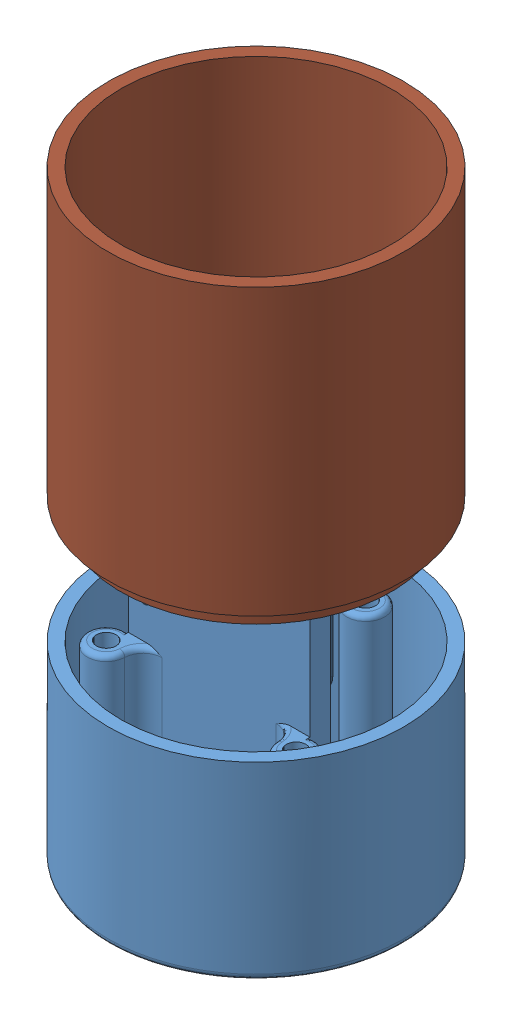
SolidWorks assembly 机器人顶部UWB基站装配, configuration 默认. Lengths in mm.
Overall size (60.56 94.97 60.56).
234 component instances, 29 part files, 4 mates.
Components (placement in the parent):
- UWB天线支架-TWR-1: UWB天线支架-TWR [默认] at (-22.1271 -22.7514 62) size (46.7 62 46.7)
- GeekUWB-TWR.step-1: GeekUWB-TWR.step [默认] at (68.161 -65.1454 64.2043) x (-1 0 0) z (0 0 -1) size (28.7 41.1 6.58)
  - R14.step-1: R14.step [默认] at origin size (0.5 1 0.35)
    - 5863272896.step-1: 5863272896.step [默认] at (77.2159 80.1371 0) x (0 1 0) z (0 0 1) size (1 0.5 0.35)
      - Terminal.step-1: Terminal.step [默认] at (-0.5 -0.25 0) size (0.25 0.5 0.35)
        - Open_CASCADE_STEP_translator_6.8_20.2.1.step-1: Open_CASCADE_STEP_translator_6.8_20.2.1.step [默认] at origin size (0.25 0.5 0.35)
      - Terminal.step-2: Terminal.step [默认] at (0.5 0.25 0) x (-1 0 0) z (0 0 1) size (0.25 0.5 0.35)
        - Open_CASCADE_STEP_translator_6.8_20.2.1.step-1: Open_CASCADE_STEP_translator_6.8_20.2.1.step [默认] at origin size (0.25 0.5 0.35)
      - Mid_Body.step-1: Mid_Body.step [默认] at (-0.5 -0.25 0) size (0.93 0.5 0.28)
      - Mark.step-1: Mark.step [默认] at (-0.25 -0.25 0.315) size (0.5 0.5 0.03)
  - C7.step-1: C7.step [默认] at origin size (1 0.5 0.5)
    - 5863272512.step-1: 5863272512.step [默认] at (78.8669 91.4399 0) x (-1 0 0) z (0 0 1) size (1 0.5 0.5)
      - Terminal-1.step-1: Terminal-1.step [默认] at (-0.5 -0.25 0) size (1 0.5 0.5)
        - Open_CASCADE_STEP_translator_6.8_54.1.1.step-1: Open_CASCADE_STEP_translator_6.8_54.1.1.step [默认] at origin size (0.25 0.5 0.5)
        - Open_CASCADE_STEP_translator_6.8_54.1.2.step-1: Open_CASCADE_STEP_translator_6.8_54.1.2.step [默认] at origin size (0.25 0.5 0.5)
      - Mid_Body-0.step-1: Mid_Body-0.step [默认] at (-0.5 -0.25 0) size (0.5 0.5 0.5)
        - Open_CASCADE_STEP_translator_6.8_54.2.1.step-1: Open_CASCADE_STEP_translator_6.8_54.2.1.step [默认] at origin size (0.5 0.5 0.5)
  - Y1.step-1: Y1.step [默认] at origin size (1.31 3.21 0.71)
    - 123123123.step-1: 123123123.step [默认] at (79.121 88.3921 0) x (0 1 0) z (0 0 1) size (3.21 1.31 0.71)
  - R7.step-1: R7.step [默认] at origin size (1 0.5 0.35)
    - 5863271360.step-1: 5863271360.step [默认] at (88.0109 97.2819 0) x (-1 0 0) z (0 0 1) size (1 0.5 0.35)
      - Terminal-2.step-1: Terminal-2.step [默认] at (-0.5 -0.25 0) size (0.25 0.5 0.35)
        - Open_CASCADE_STEP_translator_6.8_20.2.1-1.step-1: Open_CASCADE_STEP_translator_6.8_20.2.1-1.step [默认] at origin size (0.25 0.5 0.35)
      - Terminal-2.step-2: Terminal-2.step [默认] at (0.5 0.25 0) x (-1 0 0) z (0 0 1) size (0.25 0.5 0.35)
        - Open_CASCADE_STEP_translator_6.8_20.2.1-1.step-1: Open_CASCADE_STEP_translator_6.8_20.2.1-1.step [默认] at origin size (0.25 0.5 0.35)
      - Mid_Body-2.step-1: Mid_Body-2.step [默认] at (-0.5 -0.25 0) size (0.93 0.5 0.28)
      - Mark-3.step-1: Mark-3.step [默认] at (-0.25 -0.25 0.315) size (0.5 0.5 0.03)
  - R10.step-1: R10.step [默认] at origin size (1 0.5 0.35)
    - 5863271744.step-1: 5863271744.step [默认] at (101.3461 99.0601 0) x (1 0 0) z (0 0 1) size (1 0.5 0.35)
      - Terminal-3.step-1: Terminal-3.step [默认] at (-0.5 -0.25 0) size (0.25 0.5 0.35)
        - Open_CASCADE_STEP_translator_6.8_20.2.1-4.step-1: Open_CASCADE_STEP_translator_6.8_20.2.1-4.step [默认] at origin size (0.25 0.5 0.35)
      - Terminal-3.step-2: Terminal-3.step [默认] at (0.5 0.25 0) x (-1 0 0) z (0 0 1) size (0.25 0.5 0.35)
        - Open_CASCADE_STEP_translator_6.8_20.2.1-4.step-1: Open_CASCADE_STEP_translator_6.8_20.2.1-4.step [默认] at origin size (0.25 0.5 0.35)
      - Mid_Body-5.step-1: Mid_Body-5.step [默认] at (-0.5 -0.25 0) size (0.93 0.5 0.28)
      - Mark-6.step-1: Mark-6.step [默认] at (-0.25 -0.25 0.315) size (0.5 0.5 0.03)
  - R9.step-1: R9.step [默认] at origin size (1 0.5 0.35)
    - 5863271744.step-1: 5863271744.step [默认] at (101.3461 100.2031 0) x (1 0 0) z (0 0 1) size (1 0.5 0.35)
      - Terminal-3.step-1: Terminal-3.step [默认] at (-0.5 -0.25 0) size (0.25 0.5 0.35)
        - Open_CASCADE_STEP_translator_6.8_20.2.1-4.step-1: Open_CASCADE_STEP_translator_6.8_20.2.1-4.step [默认] at origin size (0.25 0.5 0.35)
      - Terminal-3.step-2: Terminal-3.step [默认] at (0.5 0.25 0) x (-1 0 0) z (0 0 1) size (0.25 0.5 0.35)
        - Open_CASCADE_STEP_translator_6.8_20.2.1-4.step-1: Open_CASCADE_STEP_translator_6.8_20.2.1-4.step [默认] at origin size (0.25 0.5 0.35)
      - Mid_Body-5.step-1: Mid_Body-5.step [默认] at (-0.5 -0.25 0) size (0.93 0.5 0.28)
      - Mark-6.step-1: Mark-6.step [默认] at (-0.25 -0.25 0.315) size (0.5 0.5 0.03)
  - R8.step-1: R8.step [默认] at origin size (1 0.5 0.35)
    - 5863271360.step-1: 5863271360.step [默认] at (82.0419 87.8839 0) x (-1 0 0) z (0 0 1) size (1 0.5 0.35)
      - Terminal-2.step-1: Terminal-2.step [默认] at (-0.5 -0.25 0) size (0.25 0.5 0.35)
        - Open_CASCADE_STEP_translator_6.8_20.2.1-1.step-1: Open_CASCADE_STEP_translator_6.8_20.2.1-1.step [默认] at origin size (0.25 0.5 0.35)
      - Terminal-2.step-2: Terminal-2.step [默认] at (0.5 0.25 0) x (-1 0 0) z (0 0 1) size (0.25 0.5 0.35)
        - Open_CASCADE_STEP_translator_6.8_20.2.1-1.step-1: Open_CASCADE_STEP_translator_6.8_20.2.1-1.step [默认] at origin size (0.25 0.5 0.35)
      - Mid_Body-2.step-1: Mid_Body-2.step [默认] at (-0.5 -0.25 0) size (0.93 0.5 0.28)
      - Mark-3.step-1: Mark-3.step [默认] at (-0.25 -0.25 0.315) size (0.5 0.5 0.03)
  - R6.step-1: R6.step [默认] at origin size (1 0.5 0.35)
    - 5863271744.step-1: 5863271744.step [默认] at (100.7111 89.2811 0) x (1 0 0) z (0 0 1) size (1 0.5 0.35)
      - Terminal-3.step-1: Terminal-3.step [默认] at (-0.5 -0.25 0) size (0.25 0.5 0.35)
        - Open_CASCADE_STEP_translator_6.8_20.2.1-4.step-1: Open_CASCADE_STEP_translator_6.8_20.2.1-4.step [默认] at origin size (0.25 0.5 0.35)
      - Terminal-3.step-2: Terminal-3.step [默认] at (0.5 0.25 0) x (-1 0 0) z (0 0 1) size (0.25 0.5 0.35)
        - Open_CASCADE_STEP_translator_6.8_20.2.1-4.step-1: Open_CASCADE_STEP_translator_6.8_20.2.1-4.step [默认] at origin size (0.25 0.5 0.35)
      - Mid_Body-5.step-1: Mid_Body-5.step [默认] at (-0.5 -0.25 0) size (0.93 0.5 0.28)
      - Mark-6.step-1: Mark-6.step [默认] at (-0.25 -0.25 0.315) size (0.5 0.5 0.03)
  - R5.step-1: R5.step [默认] at origin size (1 0.5 0.35)
    - 5863271744.step-1: 5863271744.step [默认] at (101.3461 101.3461 0) x (1 0 0) z (0 0 1) size (1 0.5 0.35)
      - Terminal-3.step-1: Terminal-3.step [默认] at (-0.5 -0.25 0) size (0.25 0.5 0.35)
        - Open_CASCADE_STEP_translator_6.8_20.2.1-4.step-1: Open_CASCADE_STEP_translator_6.8_20.2.1-4.step [默认] at origin size (0.25 0.5 0.35)
      - Terminal-3.step-2: Terminal-3.step [默认] at (0.5 0.25 0) x (-1 0 0) z (0 0 1) size (0.25 0.5 0.35)
        - Open_CASCADE_STEP_translator_6.8_20.2.1-4.step-1: Open_CASCADE_STEP_translator_6.8_20.2.1-4.step [默认] at origin size (0.25 0.5 0.35)
      - Mid_Body-5.step-1: Mid_Body-5.step [默认] at (-0.5 -0.25 0) size (0.93 0.5 0.28)
      - Mark-6.step-1: Mark-6.step [默认] at (-0.25 -0.25 0.315) size (0.5 0.5 0.03)
  - R2.step-1: R2.step [默认] at origin size (1 0.5 0.35)
    - 5863271744.step-1: 5863271744.step [默认] at (80.8991 85.4711 0) x (1 0 0) z (0 0 1) size (1 0.5 0.35)
      - Terminal-3.step-1: Terminal-3.step [默认] at (-0.5 -0.25 0) size (0.25 0.5 0.35)
        - Open_CASCADE_STEP_translator_6.8_20.2.1-4.step-1: Open_CASCADE_STEP_translator_6.8_20.2.1-4.step [默认] at origin size (0.25 0.5 0.35)
      - Terminal-3.step-2: Terminal-3.step [默认] at (0.5 0.25 0) x (-1 0 0) z (0 0 1) size (0.25 0.5 0.35)
        - Open_CASCADE_STEP_translator_6.8_20.2.1-4.step-1: Open_CASCADE_STEP_translator_6.8_20.2.1-4.step [默认] at origin size (0.25 0.5 0.35)
      - Mid_Body-5.step-1: Mid_Body-5.step [默认] at (-0.5 -0.25 0) size (0.93 0.5 0.28)
      - Mark-6.step-1: Mark-6.step [默认] at (-0.25 -0.25 0.315) size (0.5 0.5 0.03)
  - R3.step-1: R3.step [默认] at origin size (1 0.5 0.35)
    - 5863271744.step-1: 5863271744.step [默认] at (80.8991 84.4551 0) x (1 0 0) z (0 0 1) size (1 0.5 0.35)
      - Terminal-3.step-1: Terminal-3.step [默认] at (-0.5 -0.25 0) size (0.25 0.5 0.35)
        - Open_CASCADE_STEP_translator_6.8_20.2.1-4.step-1: Open_CASCADE_STEP_translator_6.8_20.2.1-4.step [默认] at origin size (0.25 0.5 0.35)
      - Terminal-3.step-2: Terminal-3.step [默认] at (0.5 0.25 0) x (-1 0 0) z (0 0 1) size (0.25 0.5 0.35)
        - Open_CASCADE_STEP_translator_6.8_20.2.1-4.step-1: Open_CASCADE_STEP_translator_6.8_20.2.1-4.step [默认] at origin size (0.25 0.5 0.35)
      - Mid_Body-5.step-1: Mid_Body-5.step [默认] at (-0.5 -0.25 0) size (0.93 0.5 0.28)
      - Mark-6.step-1: Mark-6.step [默认] at (-0.25 -0.25 0.315) size (0.5 0.5 0.03)
  - R1.step-1: R1.step [默认] at origin size (0.5 1 0.35)
    - 5863272896.step-1: 5863272896.step [默认] at (78.294 80.1531 0) x (0 1 0) z (0 0 1) size (1 0.5 0.35)
      - Terminal.step-1: Terminal.step [默认] at (-0.5 -0.25 0) size (0.25 0.5 0.35)
        - Open_CASCADE_STEP_translator_6.8_20.2.1.step-1: Open_CASCADE_STEP_translator_6.8_20.2.1.step [默认] at origin size (0.25 0.5 0.35)
      - Terminal.step-2: Terminal.step [默认] at (0.5 0.25 0) x (-1 0 0) z (0 0 1) size (0.25 0.5 0.35)
        - Open_CASCADE_STEP_translator_6.8_20.2.1.step-1: Open_CASCADE_STEP_translator_6.8_20.2.1.step [默认] at origin size (0.25 0.5 0.35)
      - Mid_Body.step-1: Mid_Body.step [默认] at (-0.5 -0.25 0) size (0.93 0.5 0.28)
      - Mark.step-1: Mark.step [默认] at (-0.25 -0.25 0.315) size (0.5 0.5 0.03)
  - R4.step-1: R4.step [默认] at origin size (1 0.5 0.35)
    - 5863271744.step-1: 5863271744.step [默认] at (80.8991 83.4391 0) x (1 0 0) z (0 0 1) size (1 0.5 0.35)
      - Terminal-3.step-1: Terminal-3.step [默认] at (-0.5 -0.25 0) size (0.25 0.5 0.35)
        - Open_CASCADE_STEP_translator_6.8_20.2.1-4.step-1: Open_CASCADE_STEP_translator_6.8_20.2.1-4.step [默认] at origin size (0.25 0.5 0.35)
      - Terminal-3.step-2: Terminal-3.step [默认] at (0.5 0.25 0) x (-1 0 0) z (0 0 1) size (0.25 0.5 0.35)
        - Open_CASCADE_STEP_translator_6.8_20.2.1-4.step-1: Open_CASCADE_STEP_translator_6.8_20.2.1-4.step [默认] at origin size (0.25 0.5 0.35)
      - Mid_Body-5.step-1: Mid_Body-5.step [默认] at (-0.5 -0.25 0) size (0.93 0.5 0.28)
      - Mark-6.step-1: Mark-6.step [默认] at (-0.25 -0.25 0.315) size (0.5 0.5 0.03)
  - R13.step-1: R13.step [默认] at origin size (1 0.5 0.35)
    - 5863271360.step-1: 5863271360.step [默认] at (98.8059 91.4399 0) x (-1 0 0) z (0 0 1) size (1 0.5 0.35)
      - Terminal-2.step-1: Terminal-2.step [默认] at (-0.5 -0.25 0) size (0.25 0.5 0.35)
        - Open_CASCADE_STEP_translator_6.8_20.2.1-1.step-1: Open_CASCADE_STEP_translator_6.8_20.2.1-1.step [默认] at origin size (0.25 0.5 0.35)
      - Terminal-2.step-2: Terminal-2.step [默认] at (0.5 0.25 0) x (-1 0 0) z (0 0 1) size (0.25 0.5 0.35)
        - Open_CASCADE_STEP_translator_6.8_20.2.1-1.step-1: Open_CASCADE_STEP_translator_6.8_20.2.1-1.step [默认] at origin size (0.25 0.5 0.35)
      - Mid_Body-2.step-1: Mid_Body-2.step [默认] at (-0.5 -0.25 0) size (0.93 0.5 0.28)
      - Mark-3.step-1: Mark-3.step [默认] at (-0.25 -0.25 0.315) size (0.5 0.5 0.03)
  - R12.step-1: R12.step [默认] at origin size (0.5 1 0.35)
    - 5863271552.step-1: 5863271552.step [默认] at (101.2191 86.7769 0) x (0 -1 0) z (0 0 1) size (1 0.5 0.35)
      - Terminal-4.step-1: Terminal-4.step [默认] at (-0.5 -0.25 0) size (0.25 0.5 0.35)
        - Open_CASCADE_STEP_translator_6.8_20.2.1-7.step-1: Open_CASCADE_STEP_translator_6.8_20.2.1-7.step [默认] at origin size (0.25 0.5 0.35)
      - Terminal-4.step-2: Terminal-4.step [默认] at (0.5 0.25 0) x (-1 0 0) z (0 0 1) size (0.25 0.5 0.35)
        - Open_CASCADE_STEP_translator_6.8_20.2.1-7.step-1: Open_CASCADE_STEP_translator_6.8_20.2.1-7.step [默认] at origin size (0.25 0.5 0.35)
      - Mid_Body-8.step-1: Mid_Body-8.step [默认] at (-0.5 -0.25 0) size (0.93 0.5 0.28)
      - Mark-9.step-1: Mark-9.step [默认] at (-0.25 -0.25 0.315) size (0.5 0.5 0.03)
  - R11.step-1: R11.step [默认] at origin size (1 0.5 0.35)
    - 5863271744.step-1: 5863271744.step [默认] at (90.9941 97.3479 0) x (1 0 0) z (0 0 1) size (1 0.5 0.35)
      - Terminal-3.step-1: Terminal-3.step [默认] at (-0.5 -0.25 0) size (0.25 0.5 0.35)
        - Open_CASCADE_STEP_translator_6.8_20.2.1-4.step-1: Open_CASCADE_STEP_translator_6.8_20.2.1-4.step [默认] at origin size (0.25 0.5 0.35)
      - Terminal-3.step-2: Terminal-3.step [默认] at (0.5 0.25 0) x (-1 0 0) z (0 0 1) size (0.25 0.5 0.35)
        - Open_CASCADE_STEP_translator_6.8_20.2.1-4.step-1: Open_CASCADE_STEP_translator_6.8_20.2.1-4.step [默认] at origin size (0.25 0.5 0.35)
      - Mid_Body-5.step-1: Mid_Body-5.step [默认] at (-0.5 -0.25 0) size (0.93 0.5 0.28)
      - Mark-6.step-1: Mark-6.step [默认] at (-0.25 -0.25 0.315) size (0.5 0.5 0.03)
  - D4.step-1: D4.step [默认] at origin size (1.01 0.5 0.45)
    - User_Library-led_0402LED0402_red_.step-1: User_Library-led_0402LED0402_red_.step [默认] at (98.6791 89.281 0) x (1 0 0) z (0 0 1) size (1.01 0.5 0.45)
  - D1.step-1: D1.step [默认] at origin size (1.01 0.5 0.45)
    - User_Library-led_0402LED0402_red_.step-1: User_Library-led_0402LED0402_red_.step [默认] at (99.3141 100.203 0) x (1 0 0) z (0 0 1) size (1.01 0.5 0.45)
  - D2.step-1: D2.step [默认] at origin size (1.01 0.5 0.45)
    - User_Library-led_0402LED0402_red_.step-1: User_Library-led_0402LED0402_red_.step [默认] at (99.3141 99.06 0) x (1 0 0) z (0 0 1) size (1.01 0.5 0.45)
  - D3.step-1: D3.step [默认] at origin size (1.01 0.5 0.45)
    - User_Library-led_0402LED0402_red_.step-1: User_Library-led_0402LED0402_red_.step [默认] at (99.3141 101.346 0) x (1 0 0) z (0 0 1) size (1.01 0.5 0.45)
  - C5.step-1: C5.step [默认] at origin size (0.5 1 0.5)
    - 5863270784.step-1: 5863270784.step [默认] at (98.6791 96.5199 0) x (0 -1 0) z (0 0 1) size (1 0.5 0.5)
      - Terminal-5.step-1: Terminal-5.step [默认] at (-0.5 -0.25 0) size (1 0.5 0.5)
        - Open_CASCADE_STEP_translator_6.8_54.1.1-10.step-1: Open_CASCADE_STEP_translator_6.8_54.1.1-10.step [默认] at origin size (0.25 0.5 0.5)
        - Open_CASCADE_STEP_translator_6.8_54.1.2-11.step-1: Open_CASCADE_STEP_translator_6.8_54.1.2-11.step [默认] at origin size (0.25 0.5 0.5)
      - Mid_Body-1.step-1: Mid_Body-1.step [默认] at (-0.5 -0.25 0) size (0.5 0.5 0.5)
        - Open_CASCADE_STEP_translator_6.8_54.2.1-12.step-1: Open_CASCADE_STEP_translator_6.8_54.2.1-12.step [默认] at origin size (0.5 0.5 0.5)
  - C6.step-1: C6.step [默认] at origin size (1 0.5 0.5)
    - 5863272512.step-1: 5863272512.step [默认] at (82.0419 88.9126 0) x (-1 0 0) z (0 0 1) size (1 0.5 0.5)
      - Terminal-1.step-1: Terminal-1.step [默认] at (-0.5 -0.25 0) size (1 0.5 0.5)
        - Open_CASCADE_STEP_translator_6.8_54.1.1.step-1: Open_CASCADE_STEP_translator_6.8_54.1.1.step [默认] at origin size (0.25 0.5 0.5)
        - Open_CASCADE_STEP_translator_6.8_54.1.2.step-1: Open_CASCADE_STEP_translator_6.8_54.1.2.step [默认] at origin size (0.25 0.5 0.5)
      - Mid_Body-0.step-1: Mid_Body-0.step [默认] at (-0.5 -0.25 0) size (0.5 0.5 0.5)
        - Open_CASCADE_STEP_translator_6.8_54.2.1.step-1: Open_CASCADE_STEP_translator_6.8_54.2.1.step [默认] at origin size (0.5 0.5 0.5)
  - C4.step-1: C4.step [默认] at origin size (1.6 0.81 0.81)
    - C0603_3D.step-1: C0603_3D.step [默认] at (100.7109 96.3929 0) x (-1 0 0) z (0 0 1) size (1.6 0.81 0.81)
  - C3.step-1: C3.step [默认] at origin size (0.5 1 0.5)
    - 5863270784.step-1: 5863270784.step [默认] at (100.0761 86.7849 0) x (0 -1 0) z (0 0 1) size (1 0.5 0.5)
      - Terminal-5.step-1: Terminal-5.step [默认] at (-0.5 -0.25 0) size (1 0.5 0.5)
        - Open_CASCADE_STEP_translator_6.8_54.1.1-10.step-1: Open_CASCADE_STEP_translator_6.8_54.1.1-10.step [默认] at origin size (0.25 0.5 0.5)
        - Open_CASCADE_STEP_translator_6.8_54.1.2-11.step-1: Open_CASCADE_STEP_translator_6.8_54.1.2-11.step [默认] at origin size (0.25 0.5 0.5)
      - Mid_Body-1.step-1: Mid_Body-1.step [默认] at (-0.5 -0.25 0) size (0.5 0.5 0.5)
        - Open_CASCADE_STEP_translator_6.8_54.2.1-12.step-1: Open_CASCADE_STEP_translator_6.8_54.2.1-12.step [默认] at origin size (0.5 0.5 0.5)
  - C2.step-1: C2.step [默认] at origin size (0.81 1.6 0.81)
    - C0603_3D.step-1: C0603_3D.step [默认] at (98.5521 86.9949 0) x (0 -1 0) z (0 0 1) size (1.6 0.81 0.81)
  - C1.step-1: C1.step [默认] at origin size (1.6 0.81 0.81)
    - C0603_3D.step-1: C0603_3D.step [默认] at (78.9939 92.8369 0) x (-1 0 0) z (0 0 1) size (1.6 0.81 0.81)
  - USB.step-1: USB.step [默认] at origin size (8.96 7.76 4.27)
    - 1.step-1: 1.step [默认] at (98.1049 122.7063 3.5) x (1 0 0) z (0 0 -1) size (8.96 7.76 4.27)
  - U3.step-1: U3.step [默认] at origin size (13.2 23 2.9)
    - DWM1000_Module.step-1: DWM1000_Module.step [默认] at (90.301 102.0509 -0.4115) x (-1 0 0) z (0 -1 0) size (13.2 2.9 23)
  - U2.step-1: U2.step [默认] at origin size (2.9 2.8 1.2)
    - PCB1.step-1: PCB1.step [默认] at (80.4724 95.505 0) x (0 1 0) z (0 0 1) size (2.8 2.9 1.2)
  - U1.step-1: U1.step [默认] at origin size (12.01 12.01 1.45)
    - LQFP64-10x10.step-1: LQFP64-10x10.step [默认] at (90.2971 89.5349 0) x (0 -1 0) z (0 0 1) size (12.01 12.01 1.45)
      - LQFP64-10X10_1_AF0_ASM.step-1: LQFP64-10X10_1_AF0_ASM.step [默认] at origin size (12.01 12.01 1.45)
        - _0_25_100.step-1: _0_25_100.step [默认] at (-5 2.75 0.75) x (0 1 0) z (0 0 1) size (0.25 1 0.8)
        - _0_25_100.step-2: _0_25_100.step [默认] at (5 -1.25 0.75) x (0 -1 0) z (0 0 1) size (0.25 1 0.8)
        - _0_25_100.step-3: _0_25_100.step [默认] at (-0.75 5 0.75) size (0.25 1 0.8)
        - _0_25_100.step-4: _0_25_100.step [默认] at (-5 -2.75 0.75) x (0 1 0) z (0 0 1) size (0.25 1 0.8)
        - _0_25_100.step-5: _0_25_100.step [默认] at (-2.75 -5 0.75) x (-1 0 0) z (0 0 1) size (0.25 1 0.8)
        - _0_25_100.step-6: _0_25_100.step [默认] at (2.75 -5 0.75) x (-1 0 0) z (0 0 1) size (0.25 1 0.8)
        - _0_25_100.step-7: _0_25_100.step [默认] at (-5 3.75 0.75) x (0 1 0) z (0 0 1) size (0.25 1 0.8)
        - _0_25_100.step-8: _0_25_100.step [默认] at (5 -2.25 0.75) x (0 -1 0) z (0 0 1) size (0.25 1 0.8)
        - _0_25_100.step-9: _0_25_100.step [默认] at (0.25 5 0.75) size (0.25 1 0.8)
        - _0_25_100.step-10: _0_25_100.step [默认] at (-5 -1.75 0.75) x (0 1 0) z (0 0 1) size (0.25 1 0.8)
        - _0_25_100.step-11: _0_25_100.step [默认] at (5 3.25 0.75) x (0 -1 0) z (0 0 1) size (0.25 1 0.8)
        - _0_25_100.step-12: _0_25_100.step [默认] at (-0.25 -5 0.75) x (-1 0 0) z (0 0 1) size (0.25 1 0.8)
        - _0_25_100.step-13: _0_25_100.step [默认] at (5 -3.25 0.75) x (0 -1 0) z (0 0 1) size (0.25 1 0.8)
        - _0_25_100.step-14: _0_25_100.step [默认] at (1.25 5 0.75) size (0.25 1 0.8)
        - _0_25_100.step-15: _0_25_100.step [默认] at (-5 -0.75 0.75) x (0 1 0) z (0 0 1) size (0.25 1 0.8)
        - _0_25_100.step-16: _0_25_100.step [默认] at (5 2.25 0.75) x (0 -1 0) z (0 0 1) size (0.25 1 0.8)
        - _0_25_100.step-17: _0_25_100.step [默认] at (-3.25 -5 0.75) x (-1 0 0) z (0 0 1) size (0.25 1 0.8)
        - _0_25_100.step-18: _0_25_100.step [默认] at (2.25 -5 0.75) x (-1 0 0) z (0 0 1) size (0.25 1 0.8)
        - _0_25_100.step-19: _0_25_100.step [默认] at (2.25 5 0.75) size (0.25 1 0.8)
        - _0_25_100.step-20: _0_25_100.step [默认] at (-5 0.25 0.75) x (0 1 0) z (0 0 1) size (0.25 1 0.8)
        - _0_25_100.step-21: _0_25_100.step [默认] at (5 1.25 0.75) x (0 -1 0) z (0 0 1) size (0.25 1 0.8)
        - _0_25_100.step-22: _0_25_100.step [默认] at (-3.25 5 0.75) size (0.25 1 0.8)
        - _0_25_100.step-23: _0_25_100.step [默认] at (-0.75 -5 0.75) x (-1 0 0) z (0 0 1) size (0.25 1 0.8)
        - _0_25_100.step-24: _0_25_100.step [默认] at (3.25 5 0.75) size (0.25 1 0.8)
        - _0_25_100.step-25: _0_25_100.step [默认] at (-5 1.25 0.75) x (0 1 0) z (0 0 1) size (0.25 1 0.8)
        - _0_25_100.step-26: _0_25_100.step [默认] at (5 0.25 0.75) x (0 -1 0) z (0 0 1) size (0.25 1 0.8)
        - _0_25_100.step-27: _0_25_100.step [默认] at (-2.25 5 0.75) size (0.25 1 0.8)
        - _0_25_100.step-28: _0_25_100.step [默认] at (-3.75 -5 0.75) x (-1 0 0) z (0 0 1) size (0.25 1 0.8)
        - _0_25_100.step-29: _0_25_100.step [默认] at (1.75 -5 0.75) x (-1 0 0) z (0 0 1) size (0.25 1 0.8)
        - _0_25_100.step-30: _0_25_100.step [默认] at (-5 2.25 0.75) x (0 1 0) z (0 0 1) size (0.25 1 0.8)
        - _0_25_100.step-31: _0_25_100.step [默认] at (5 -0.75 0.75) x (0 -1 0) z (0 0 1) size (0.25 1 0.8)
        - _0_25_100.step-32: _0_25_100.step [默认] at (-1.25 5 0.75) size (0.25 1 0.8)
        - _0_25_100.step-33: _0_25_100.step [默认] at (-5 -3.25 0.75) x (0 1 0) z (0 0 1) size (0.25 1 0.8)
        - _0_25_100.step-34: _0_25_100.step [默认] at (-1.25 -5 0.75) x (-1 0 0) z (0 0 1) size (0.25 1 0.8)
        - LQFP64_10X10___A.step-1: LQFP64_10X10___A.step [默认] at origin size (10 10 1.4)
        - _0_25_100.step-35: _0_25_100.step [默认] at (-5 3.25 0.75) x (0 1 0) z (0 0 1) size (0.25 1 0.8)
        - _0_25_100.step-36: _0_25_100.step [默认] at (5 -1.75 0.75) x (0 -1 0) z (0 0 1) size (0.25 1 0.8)
        - _0_25_100.step-37: _0_25_100.step [默认] at (-0.25 5 0.75) size (0.25 1 0.8)
        - _0_25_100.step-38: _0_25_100.step [默认] at (-5 -2.25 0.75) x (0 1 0) z (0 0 1) size (0.25 1 0.8)
        - _0_25_100.step-39: _0_25_100.step [默认] at (5 3.75 0.75) x (0 -1 0) z (0 0 1) size (0.25 1 0.8)
        - _0_25_100.step-40: _0_25_100.step [默认] at (1.25 -5 0.75) x (-1 0 0) z (0 0 1) size (0.25 1 0.8)
        - _0_25_100.step-41: _0_25_100.step [默认] at (5 -2.75 0.75) x (0 -1 0) z (0 0 1) size (0.25 1 0.8)
        - _0_25_100.step-42: _0_25_100.step [默认] at (0.75 5 0.75) size (0.25 1 0.8)
        - _0_25_100.step-43: _0_25_100.step [默认] at (-5 -1.25 0.75) x (0 1 0) z (0 0 1) size (0.25 1 0.8)
        - _0_25_100.step-44: _0_25_100.step [默认] at (5 2.75 0.75) x (0 -1 0) z (0 0 1) size (0.25 1 0.8)
        - _0_25_100.step-45: _0_25_100.step [默认] at (-1.75 -5 0.75) x (-1 0 0) z (0 0 1) size (0.25 1 0.8)
        - _0_25_100.step-46: _0_25_100.step [默认] at (3.75 -5 0.75) x (-1 0 0) z (0 0 1) size (0.25 1 0.8)
        - _0_25_100.step-47: _0_25_100.step [默认] at (5 -3.75 0.75) x (0 -1 0) z (0 0 1) size (0.25 1 0.8)
        - _0_25_100.step-48: _0_25_100.step [默认] at (1.75 5 0.75) size (0.25 1 0.8)
        - _0_25_100.step-49: _0_25_100.step [默认] at (-5 -0.25 0.75) x (0 1 0) z (0 0 1) size (0.25 1 0.8)
        - _0_25_100.step-50: _0_25_100.step [默认] at (5 1.75 0.75) x (0 -1 0) z (0 0 1) size (0.25 1 0.8)
        - _0_25_100.step-51: _0_25_100.step [默认] at (-3.75 5 0.75) size (0.25 1 0.8)
        - _0_25_100.step-52: _0_25_100.step [默认] at (0.75 -5 0.75) x (-1 0 0) z (0 0 1) size (0.25 1 0.8)
        - _0_25_100.step-53: _0_25_100.step [默认] at (2.75 5 0.75) size (0.25 1 0.8)
        - _0_25_100.step-54: _0_25_100.step [默认] at (-5 0.75 0.75) x (0 1 0) z (0 0 1) size (0.25 1 0.8)
        - _0_25_100.step-55: _0_25_100.step [默认] at (5 0.75 0.75) x (0 -1 0) z (0 0 1) size (0.25 1 0.8)
        - _0_25_100.step-56: _0_25_100.step [默认] at (-2.75 5 0.75) size (0.25 1 0.8)
        - _0_25_100.step-57: _0_25_100.step [默认] at (-2.25 -5 0.75) x (-1 0 0) z (0 0 1) size (0.25 1 0.8)
        - _0_25_100.step-58: _0_25_100.step [默认] at (3.25 -5 0.75) x (-1 0 0) z (0 0 1) size (0.25 1 0.8)
        - _0_25_100.step-59: _0_25_100.step [默认] at (3.75 5 0.75) size (0.25 1 0.8)
        - _0_25_100.step-60: _0_25_100.step [默认] at (-5 1.75 0.75) x (0 1 0) z (0 0 1) size (0.25 1 0.8)
        - _0_25_100.step-61: _0_25_100.step [默认] at (5 -0.25 0.75) x (0 -1 0) z (0 0 1) size (0.25 1 0.8)
        - _0_25_100.step-62: _0_25_100.step [默认] at (-1.75 5 0.75) size (0.25 1 0.8)
        - _0_25_100.step-63: _0_25_100.step [默认] at (-5 -3.75 0.75) x (0 1 0) z (0 0 1) size (0.25 1 0.8)
        - _0_25_100.step-64: _0_25_100.step [默认] at (0.25 -5 0.75) x (-1 0 0) z (0 0 1) size (0.25 1 0.8)
  - Board.step-1: Board.step [默认] at origin size (28.7 31.37 0.41)
- UWB透明保护壳-1: UWB透明保护壳 [默认] at (-22.1271 27.2147 62) x (0.930564 0 0.36613) z (-0.36613 0 0.930564) size (46.7 47.5 46.7)
Mates (geometry in assembly coordinates):
- 重合2: coincident anti-aligned: plane of UWB天线支架-TWR-1 through (-36.4692 39.2486 64.6158) normal (0 0 -1); plane of GeekUWB-TWR.step-1/Board.step-1 through (-10.234 7.9176 64.6158) normal (0 0 1)
- 重合3: coincident aligned: plane of UWB天线支架-TWR-1 through (-22.1271 39.2486 62) normal (0 1 0); plane of GeekUWB-TWR.step-1/Board.step-1 through (-10.706 39.2486 64.6158) normal (0 1 0)
- 重合4: coincident aligned: plane of UWB天线支架-TWR-1 through (-7.785 39.2486 64.6158) normal (1 0 0); plane of GeekUWB-TWR.step-1/Board.step-1 through (-7.785 10.8006 64.6158) normal (1 0 0)
- 同心1: concentric aligned: cylinder of UWB天线支架-TWR-1 through (-22.1271 7.2486 62) axis (0 -1 0) radius 23.35; cylinder of UWB透明保护壳-1 through (-22.1271 72.2147 62) axis (0 -1 0) radius 23.35
